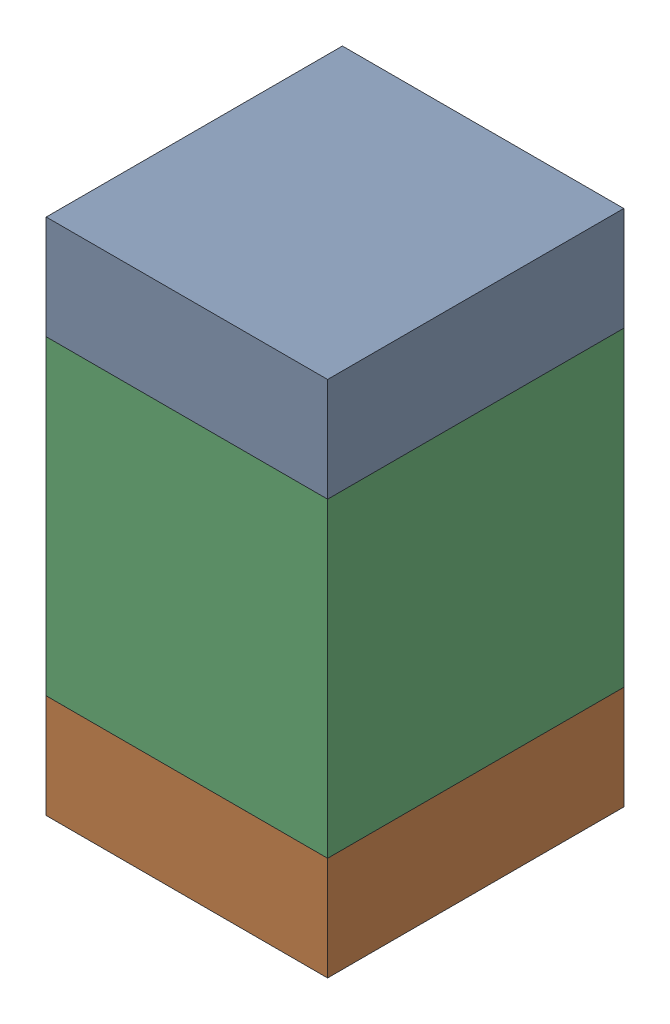
SolidWorks assembly C10-1, configuration Default. Lengths in mm.
Overall size (0.95 1.75 1).
6 component instances, 2 part files, 0 mates.
Components (placement in the parent):
- 959208664-1-1: 959208664-1 [Default] at (109.7632 77.5843 0) size (0.95 0.35 1)
  - Extruded-45-1: Extruded-45 [Default] at origin size (0.95 0.35 1)
- 959208664-1-2: 959208664-1 [Default] at (109.7632 76.1843 0) size (0.95 0.35 1)
  - Extruded-45-1: Extruded-45 [Default] at origin size (0.95 0.35 1)
- 959208528-1-1: 959208528-1 [Default] at (109.7632 76.8843 0) size (0.95 1.05 1)
  - Extruded-46-1: Extruded-46 [Default] at origin size (0.95 1.05 1)
